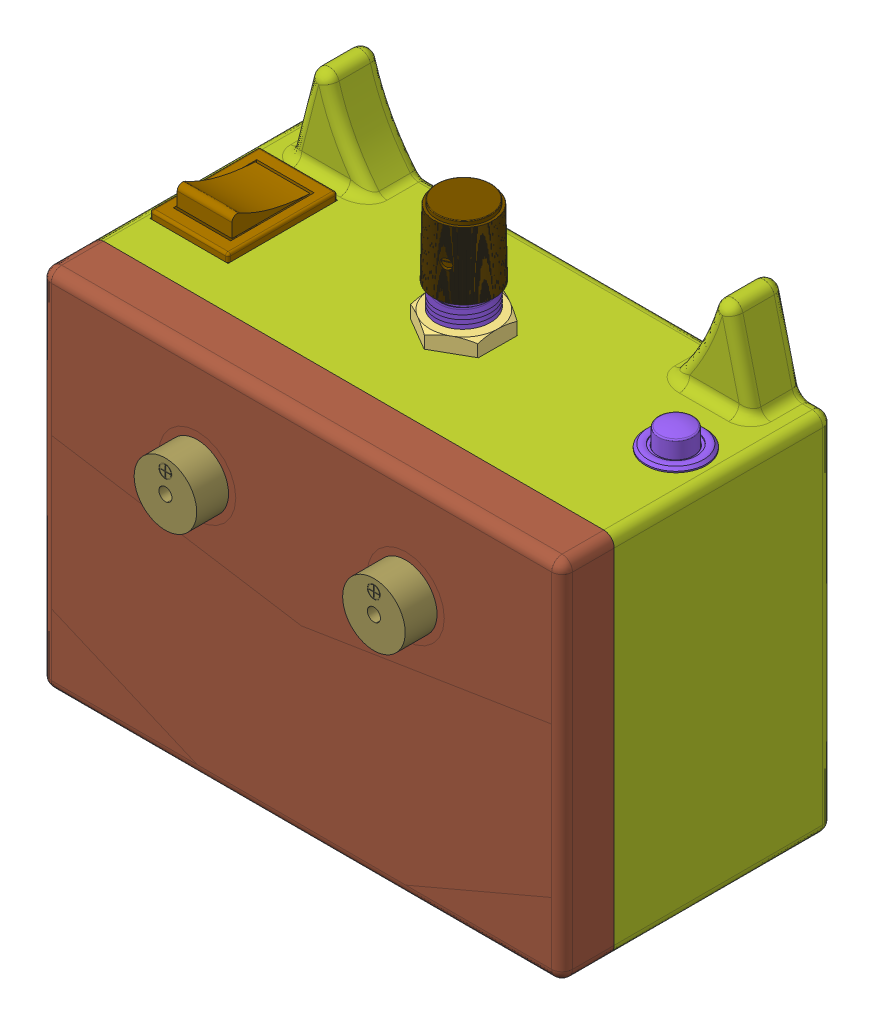
SolidWorks assembly Audio Output, configuration Default. Lengths in mm.
Overall size (102 91.24 58.1).
102 component instances, 40 part files, 22 mates.
Components (placement in the parent):
- PCB1.step-1: PCB1.step [Default] at (26.2994 -25.319 55.249) x (0 1 0) z (0 0 1) size (50.05 60.08 30.02)
  - Board.step-1: Board.step [Default] at origin size (50.05 60.08 0.41)
    - Open CASCADE STEP translator 6.8 1.1.1.step-1: Open CASCADE STEP translator 6.8 1.1.1.step [Default] at (0 0 -0.4115) size (50.05 60.08 0.41)
  - JST4.step-1: JST4.step [Default] at origin size (7.4 5.75 10.4)
    - Conn_JST_B2B-XH-A_LF_SN_eec.step-1: Conn_JST_B2B-XH-A_LF_SN_eec.step [Default] at (42.2 27 0) size (7.4 5.75 10.4)
      - 1.step-1: 1.step [Default] at (0 0.025 0) x (-1 0 0) z (0 1 0) size (7.4 10.4 5.75)
        - 1-0.step-1: 1-0.step [Default] at origin size (3.14 10.2 0.64)
        - B2B-XH-A.step-1: B2B-XH-A.step [Default] at origin size (7.4 7 5.75)
        - JST_Logo_adjustable.step-1: JST_Logo_adjustable.step [Default] at (-1.7267 5.5034 2.841) size (0.85 2.3 0.01)
  - U2.step-1: U2.step [Default] at origin size (4.51 10.4 30.02)
    - 5981934816.step-1: 5981934816.step [Default] at (24.525 10.615 0) x (1 0 0) z (0 0 1) size (1.3 10.4 0)
      - Extruded.step-1: Extruded.step [Default] at origin size (1.3 10.4 0)
    - L7805ACV.step-1: L7805ACV.step [Default] at (26.598 10.615 0) x (0 1 0) z (1 0 0) size (10.1 30.02 4.45)
  - XTAL1.step-1: XTAL1.step [Default] at origin size (4.65 11.36 3.61)
    - 5981933456.step-1: 5981933456.step [Default] at (7.9501 28.7399 0) size (4.65 11.36 1.01)
      - Extruded-1.step-1: Extruded-1.step [Default] at origin size (4.65 11.36 1.01)
    - 5981933376.step-1: 5981933376.step [Default] at (7.9499 28.7399 1) size (3.7 10.05 2.6)
      - Extruded-2.step-1: Extruded-2.step [Default] at origin size (3.7 10.05 2.6)
  - U1.step-1: U1.step [Default] at origin size (9.68 34.6 7.3)
    - atmega328p-pu.step-1: atmega328p-pu.step [Default] at (18.5 51.4 0) x (0 -1 0) z (-1 0 0) size (34.6 7.3 9.68)
  - R2.step-1: R2.step [Default] at origin size (2.5 7 2.5)
    - 5981932096.step-1: 5981932096.step [Default] at (7.5999 50.5249 1.25) x (1 0 0) z (0 -1 0) size (2.5 2.5 7)
      - Cylinder.step-1: Cylinder.step [Default] at origin size (2.5 2.5 7)
  - R1.step-1: R1.step [Default] at origin size (7 2.5 2.5)
    - 5981930976.step-1: 5981930976.step [Default] at (38.0251 34.4999 1.25) x (0 1 0) z (1 0 0) size (2.5 2.5 7)
      - Cylinder-3.step-1: Cylinder-3.step [Default] at origin size (2.5 2.5 7)
  - Q1.step-1: Q1.step [Default] at origin size (3.05 4.08 12.8)
    - BC547-B.step-1: BC547-B.step [Default] at (39.7 49.2764 5) x (0 -1 0) z (0 0 -1) size (4.08 3.05 12.8)
  - JST3.step-1: JST3.step [Default] at origin size (3.4 8.75 6.85)
    - Conn_Harwin_M30-6100646_eec.step-1: Conn_Harwin_M30-6100646_eec.step [Default] at (30.37 24.2 0) x (0 1 0) z (0 0 1) size (8.75 3.4 6.85)
      - M30-610XXXX_MOULDING.step-1: M30-610XXXX_MOULDING.step [Default] at (4.375 1.7 4.3) size (8.75 3.4 4.55)
      - M30-610XXXX_PIN.step-1: M30-610XXXX_PIN.step [Default] at (-2.95 0.675 -2.3) x (-1 0 0) z (0 0 1) size (0.35 0.35 6)
      - M30-610XXXX_PIN.step-2: M30-610XXXX_PIN.step [Default] at (-1.7 0.675 -2.3) x (-1 0 0) z (0 0 1) size (0.35 0.35 6)
      - M30-610XXXX_PIN.step-3: M30-610XXXX_PIN.step [Default] at (-0.45 0.675 -2.3) x (-1 0 0) z (0 0 1) size (0.35 0.35 6)
      - M30-610XXXX_PIN.step-4: M30-610XXXX_PIN.step [Default] at (0.8 0.675 -2.3) x (-1 0 0) z (0 0 1) size (0.35 0.35 6)
      - M30-610XXXX_PIN.step-5: M30-610XXXX_PIN.step [Default] at (2.05 0.675 -2.3) x (-1 0 0) z (0 0 1) size (0.35 0.35 6)
      - M30-610XXXX_PIN.step-6: M30-610XXXX_PIN.step [Default] at (3.3 0.675 -2.3) x (-1 0 0) z (0 0 1) size (0.35 0.35 6)
      - Harwin.step-1: Harwin.step [Default] at (-3.7429 -1.6985 2.1984) x (1 0 0) z (0 -1 0) size (2.66 0.49 0)
  - JST2.step-1: JST2.step [Default] at origin size (7.4 5.75 10.4)
    - Conn_JST_B2B-XH-A_LF_SN_eec.step-1: Conn_JST_B2B-XH-A_LF_SN_eec.step [Default] at (29.475 48.15 0) size (7.4 5.75 10.4)
      - 1.step-1: 1.step [Default] at (0 0.025 0) x (-1 0 0) z (0 1 0) size (7.4 10.4 5.75)
        - 1-0.step-1: 1-0.step [Default] at origin size (3.14 10.2 0.64)
        - B2B-XH-A.step-1: B2B-XH-A.step [Default] at origin size (7.4 7 5.75)
        - JST_Logo_adjustable.step-1: JST_Logo_adjustable.step [Default] at (-1.7267 5.5034 2.841) size (0.85 2.3 0.01)
  - JST1.step-1: JST1.step [Default] at origin size (7.4 5.75 10.4)
    - Conn_JST_B2B-XH-A_LF_SN_eec.step-1: Conn_JST_B2B-XH-A_LF_SN_eec.step [Default] at (15.625 8.65 0) x (-1 0 0) z (0 0 1) size (7.4 5.75 10.4)
      - 1.step-1: 1.step [Default] at (0 0.025 0) x (-1 0 0) z (0 1 0) size (7.4 10.4 5.75)
        - 1-0.step-1: 1-0.step [Default] at origin size (3.14 10.2 0.64)
        - B2B-XH-A.step-1: B2B-XH-A.step [Default] at origin size (7.4 7 5.75)
        - JST_Logo_adjustable.step-1: JST_Logo_adjustable.step [Default] at (-1.7267 5.5034 2.841) size (0.85 2.3 0.01)
  - C6.step-1: C6.step [Default] at origin size (8 8 14.5)
    - Aluminum_electrolytic_capacitor_radial_D8_H11.5_PinD0.6_Pitch3.5_nominal_black.step-1: Aluminum_electrolytic_capacitor_radial_D8_H11.5_PinD0.6_Pitch3.5_nominal_black.step [Default] at (42.175 17.25 0) x (-1 0 0) z (0 0 1) size (1.1 2.07 11.1)
    - Aluminum_electrolytic_capacitor_radial_D8_H11.5_PinD0.6_Pitch3.5_nominal_black-4.step-1: Aluminum_electrolytic_capacitor_radial_D8_H11.5_PinD0.6_Pitch3.5_nominal_black-4.step [Default] at (42.175 17.25 0) x (-1 0 0) z (0 0 1) size (7.86 8 11.1)
    - Aluminum_electrolytic_capacitor_radial_D8_H11.5_PinD0.6_Pitch3.5_nominal_black-5.step-1: Aluminum_electrolytic_capacitor_radial_D8_H11.5_PinD0.6_Pitch3.5_nominal_black-5.step [Default] at (42.175 17.25 0) x (-1 0 0) z (0 0 1) size (7.8 7.8 10.9)
    - Aluminum_electrolytic_capacitor_radial_D8_H11.5_PinD0.6_Pitch3.5_nominal_black-6.step-1: Aluminum_electrolytic_capacitor_radial_D8_H11.5_PinD0.6_Pitch3.5_nominal_black-6.step [Default] at (42.175 17.25 0) x (-1 0 0) z (0 0 1) size (7.4 7.4 1.6)
    - Aluminum_electrolytic_capacitor_radial_D8_H11.5_PinD0.6_Pitch3.5_nominal_black-7.step-1: Aluminum_electrolytic_capacitor_radial_D8_H11.5_PinD0.6_Pitch3.5_nominal_black-7.step [Default] at (42.175 17.25 0) x (-1 0 0) z (0 0 1) size (4.1 0.6 3)
  - C5.step-1: C5.step [Default] at origin size (8 8 14.5)
    - Aluminum_electrolytic_capacitor_radial_D8_H11.5_PinD0.6_Pitch3.5_nominal_black.step-1: Aluminum_electrolytic_capacitor_radial_D8_H11.5_PinD0.6_Pitch3.5_nominal_black.step [Default] at (35.75 10.125 0) size (1.1 2.07 11.1)
    - Aluminum_electrolytic_capacitor_radial_D8_H11.5_PinD0.6_Pitch3.5_nominal_black-4.step-1: Aluminum_electrolytic_capacitor_radial_D8_H11.5_PinD0.6_Pitch3.5_nominal_black-4.step [Default] at (35.75 10.125 0) size (7.86 8 11.1)
    - Aluminum_electrolytic_capacitor_radial_D8_H11.5_PinD0.6_Pitch3.5_nominal_black-5.step-1: Aluminum_electrolytic_capacitor_radial_D8_H11.5_PinD0.6_Pitch3.5_nominal_black-5.step [Default] at (35.75 10.125 0) size (7.8 7.8 10.9)
    - Aluminum_electrolytic_capacitor_radial_D8_H11.5_PinD0.6_Pitch3.5_nominal_black-6.step-1: Aluminum_electrolytic_capacitor_radial_D8_H11.5_PinD0.6_Pitch3.5_nominal_black-6.step [Default] at (35.75 10.125 0) size (7.4 7.4 1.6)
    - Aluminum_electrolytic_capacitor_radial_D8_H11.5_PinD0.6_Pitch3.5_nominal_black-7.step-1: Aluminum_electrolytic_capacitor_radial_D8_H11.5_PinD0.6_Pitch3.5_nominal_black-7.step [Default] at (35.75 10.125 0) size (4.1 0.6 3)
  - C3.step-1: C3.step [Default] at origin size (8 8 14.5)
    - Aluminum_electrolytic_capacitor_radial_D8_H11.5_PinD0.6_Pitch3.5_nominal_black.step-1: Aluminum_electrolytic_capacitor_radial_D8_H11.5_PinD0.6_Pitch3.5_nominal_black.step [Default] at (30.75 38.1 0) x (0 1 0) z (0 0 1) size (1.1 2.07 11.1)
    - Aluminum_electrolytic_capacitor_radial_D8_H11.5_PinD0.6_Pitch3.5_nominal_black-4.step-1: Aluminum_electrolytic_capacitor_radial_D8_H11.5_PinD0.6_Pitch3.5_nominal_black-4.step [Default] at (30.75 38.1 0) x (0 1 0) z (0 0 1) size (7.86 8 11.1)
    - Aluminum_electrolytic_capacitor_radial_D8_H11.5_PinD0.6_Pitch3.5_nominal_black-5.step-1: Aluminum_electrolytic_capacitor_radial_D8_H11.5_PinD0.6_Pitch3.5_nominal_black-5.step [Default] at (30.75 38.1 0) x (0 1 0) z (0 0 1) size (7.8 7.8 10.9)
    - Aluminum_electrolytic_capacitor_radial_D8_H11.5_PinD0.6_Pitch3.5_nominal_black-6.step-1: Aluminum_electrolytic_capacitor_radial_D8_H11.5_PinD0.6_Pitch3.5_nominal_black-6.step [Default] at (30.75 38.1 0) x (0 1 0) z (0 0 1) size (7.4 7.4 1.6)
    - Aluminum_electrolytic_capacitor_radial_D8_H11.5_PinD0.6_Pitch3.5_nominal_black-7.step-1: Aluminum_electrolytic_capacitor_radial_D8_H11.5_PinD0.6_Pitch3.5_nominal_black-7.step [Default] at (30.75 38.1 0) x (0 1 0) z (0 0 1) size (4.1 0.6 3)
  - C2.step-1: C2.step [Default] at origin size (5.5 2.51 10)
    - Cap_Murata_RCE5C2A3R0C0K1H03B_eec.step-1: Cap_Murata_RCE5C2A3R0C0K1H03B_eec.step [Default] at (7.8 18.95 0) x (1 0 0) z (0 0 1) size (5.5 2.51 10)
      - body.step-1: body.step [Default] at origin size (3.6 2.5 4.1)
      - leads.step-1: leads.step [Default] at origin size (5.5 0.5 6.65)
      - logo.step-1: logo.step [Default] at (0 -1.25 8.5) x (1 0 0) z (0 -1 0) size (1.98 0.46 0.01)
  - C1.step-1: C1.step [Default] at origin size (5.5 2.51 10)
    - Cap_Murata_RCE5C2A3R0C0K1H03B_eec.step-1: Cap_Murata_RCE5C2A3R0C0K1H03B_eec.step [Default] at (8.3 38.2 0) x (1 0 0) z (0 0 1) size (5.5 2.51 10)
      - body.step-1: body.step [Default] at origin size (3.6 2.5 4.1)
      - leads.step-1: leads.step [Default] at origin size (5.5 0.5 6.65)
      - logo.step-1: logo.step [Default] at (0 -1.25 8.5) x (1 0 0) z (0 -1 0) size (1.98 0.46 0.01)
  - Free-Models.step-1: Free-Models.step [Default] at origin size (10.56 2.5 4.8)
    - Diode_1N4001.step-1: Diode_1N4001.step [Default] at (44.28 43.65 0) x (-1 0 0) z (0 0 1) size (10.56 2.5 4.8)
- Part49^Audio Output-1: Part49^Audio Output [Default] at (26.2994 -25.319 55.249) x (0 1 0) z (0 0 1) size (86.95 102 42.04) (virtual)
- Bouton poussoir-2: Bouton poussoir [Défaut] at (37.5441 27.181 52.749) size (11.58 13 11.58)
- 64_Switch.step-1: 64_Switch.step [Default] at (-51.0981 24.181 63.0135) x (0 0 -1) z (1 0 0) size (23 26.97 15)
- BATTARY HOLDER-1: BATTARY HOLDER [По умолчанию] at (-3.7956 -0.254 51.249) x (-1 0 0) z (0 -1 0) size (54.61 19.5 29.97)
- Part1^Audio Output-1: Part1^Audio Output [Default] at (26.2994 -25.319 73.249) x (0 1 0) z (0 0 1) size (70 100 27.75) (virtual)
- TMB12A05.step-1: TMB12A05.step [Default] at (-23.7756 10.891 79.839) size (12 12 11.85)
- TMB12A05.step-2: TMB12A05.step [Default] at (16.2244 10.891 79.839) size (12 12 11.85)
- 100 ohm Sigle Potentiometer Assembly.STEP-1: 100 ohm Sigle Potentiometer Assembly.STEP [Default] at (-2.4938 19.2483 61.2667) x (-0.926821 0 0.375502) z (0 -1 0) size (25.4 26.22 29.59)
  - PCB.STEP-1: PCB.STEP [Default] at (-2.7005 7.9259 -11.5277) size (16.64 19.94 1.27)
  - Plate.STEP-1: Plate.STEP [Default] at (-2.7005 7.9259 -12.1627) size (17.02 10.92 0.64)
  - Wire_Tab.STEP-1: Wire_Tab.STEP [Default] at (-5.8755 14.4664 -10.2577) x (0 1 0) z (0 0 1) size (6.98 3.81 4.44)
  - Wire_Tab.STEP-2: Wire_Tab.STEP [Default] at (-0.7955 14.4664 -10.2577) x (0 1 0) z (0 0 1) size (6.98 3.81 4.44)
  - Wire_Tab.STEP-3: Wire_Tab.STEP [Default] at (4.2845 14.4664 -10.2577) x (0 1 0) z (0 0 1) size (6.98 3.81 4.44)
  - Rivet.STEP-1: Rivet.STEP [Default] at (-7.7805 16.3714 -9.6227) x (-0.923728 -0.383049 0) z (0 0 -1) size (2.54 3.49 2.22)
  - Rivet.STEP-2: Rivet.STEP [Default] at (-2.7005 16.3714 -9.6227) x (-0.923728 -0.383049 0) z (0 0 -1) size (2.54 3.49 2.22)
  - Rivet.STEP-3: Rivet.STEP [Default] at (2.3795 16.3714 -9.6227) x (-0.923728 -0.383049 0) z (0 0 -1) size (2.54 3.49 2.22)
  - Barrell2.STEP-1: Barrell2.STEP [Default] at (-2.7005 7.9259 -21.6877) size (10.47 10.4 9.53)
  - Potentiometer Knob.STEP-1: Potentiometer Knob.STEP [Default] at (-10.5959 -2.0877 -35.9117) x (-1 0 0) z (0 0 -1) size (11.86 13.59 13.46)
  - Shaft.STEP-1: Shaft.STEP [Default] at (-2.7005 7.9259 -14.3217) x (-0.923728 -0.383049 0) z (0 0 -1) size (5.97 5.97 23.75)
  - Washer^100 ohm Sigle Potentiometer Assembly.STEP-1: Washer^100 ohm Sigle Potentiometer Assembly.STEP [Default] at (-2.7005 7.9259 -13.4327) x (-1 0 0) z (0 0 -1) size (14.25 14.25 0.89)
  - hex nut jam_am_B18.2.4.5M - Hex jam nut,  M8 x 1.25 --D-N.STEP-1: hex nut jam_am_B18.2.4.5M - Hex jam nut,  M8 x 1.25 --D-N.STEP [Default] at (-2.7005 7.9259 -18.3217) x (0.923728 0.383049 0) z (0 0 -1) size (15.02 15.02 4.01)
  - Level Indicator Plate^100 ohm Sigle Potentiometer Assembly.STEP-1: Level Indicator Plate^100 ohm Sigle Potentiometer Assembly.STEP [Default] at (-2.7005 7.9259 -12.1627) x (-1 0 0) z (0 0 -1) size (25.4 25.4 1.27)
Mates (geometry in assembly coordinates):
- InPlace1: in place: plane of PCB1.step-1/Board.step-1/Open CASCADE STEP translator 6.8 1.1.1.step-1 through (26.2994 -25.319 55.249) normal (0 0 1); plane of ? through (0 0 55.249) normal (0 0 1); moOrthogonalPlaneRef_w of PCB1.step-1/Board.step-1/Open CASCADE STEP translator 6.8 1.1.1.step-1 through (26.2994 -25.319 55.249) normal (0 0 1); plane of ? through (0 0 55.249) normal (0 1 0); plane of PCB1.step-1/Board.step-1/Open CASCADE STEP translator 6.8 1.1.1.step-1 through (26.2994 -25.319 55.249) normal (0 0 1); plane of ? through (0 0 55.249) normal (1 0 0); plane of PCB1.step-1/Board.step-1/Open CASCADE STEP translator 6.8 1.1.1.step-1 through (26.2994 -25.319 55.249) normal (0 0 1); unknown of Part49^Audio Output-1
- Coincident1: coincident aligned: plane of PCB1.step-1/Board.step-1/Open CASCADE STEP translator 6.8 1.1.1.step-1; plane of Part49^Audio Output-1
- Coincident2: coincident aligned: moOrthogonalPlaneRef_w of PCB1.step-1/Board.step-1/Open CASCADE STEP translator 6.8 1.1.1.step-1 through (26.2994 -25.319 55.249) normal (-1 0 0); plane of Part49^Audio Output-1 through (26.2994 -25.319 55.249) normal (-1 0 0)
- Coincident3: coincident anti-aligned: moOrthogonalPlaneRef_w of PCB1.step-1/Board.step-1/Open CASCADE STEP translator 6.8 1.1.1.step-1 through (26.2994 -25.319 55.249) normal (0 -1 0); plane of Part49^Audio Output-1 through (26.2994 -25.319 55.249) normal (0 1 0)
- Concentric2: concentric anti-aligned: cylinder of Part49^Audio Output-1 through (37.5441 29.681 52.749) axis (0 1 0) radius 5.125; cylinder of Bouton poussoir-2 through (37.5441 34.681 52.749) axis (0 -1 0) radius 5
- Coincident12: coincident anti-aligned: plane of Part49^Audio Output-1 through (-53.7756 34.681 73.249) normal (0 1 0); plane of Bouton poussoir-2 through (37.5441 34.681 52.749) normal (0 -1 0)
- Coincident23: coincident anti-aligned: plane of Part49^Audio Output-1 through (-53.7756 34.681 73.249) normal (0 1 0); plane of 64_Switch.step-1 through (-51.0981 34.681 44.0135) normal (0 -1 0)
- Coincident27: coincident anti-aligned: line of Part49^Audio Output-1 through (-51.1081 34.681 65.0135) axis (1 0 0); line of 64_Switch.step-1 through (-36.5981 34.681 65.0135) axis (-1 0 0)
- Coincident28: coincident aligned: line of Part49^Audio Output-1 through (-36.0981 34.681 65.0135) axis (0 0 -1); line of 64_Switch.step-1 through (-36.0981 34.681 64.5135) axis (0 0 -1)
- Coincident32: coincident anti-aligned: plane of Part49^Audio Output-1 through (26.2994 -25.319 51.249) normal (0 0 -1); plane of BATTARY HOLDER-1 through (-3.7956 -0.254 51.249) normal (0 0 1)
- Coincident33: coincident anti-aligned: plane of Part49^Audio Output-1 through (25.5542 14.731 53.249) normal (0 -1 0); plane of BATTARY HOLDER-1 through (23.5094 14.731 48.749) normal (0 1 0)
- Coincident34: coincident anti-aligned: plane of Part49^Audio Output-1 through (-31.1006 16.731 53.249) normal (1 0 0); plane of BATTARY HOLDER-1 through (-31.1006 14.731 48.749) normal (-1 0 0)
- InPlace2: in place: plane of Part49^Audio Output-1 through (26.2994 -25.319 73.249) normal (0 0 1); plane of ? through (0 0 73.249) normal (0 0 1); plane of Part49^Audio Output-1 through (26.2994 -25.319 73.249) normal (0 0 1); plane of ? through (0 0 73.249) normal (0 1 0); plane of Part49^Audio Output-1 through (26.2994 -25.319 73.249) normal (0 0 1); plane of ? through (0 0 73.249) normal (1 0 0); plane of Part49^Audio Output-1 through (26.2994 -25.319 73.249) normal (0 0 1); unknown of Part1^Audio Output-1
- Coincident35: coincident aligned: plane of Part49^Audio Output-1; plane of Part1^Audio Output-1
- Coincident36: coincident aligned: moOrthogonalPlaneRef_w of Part49^Audio Output-1 through (26.2994 -25.319 73.249) normal (-1 0 0); plane of Part1^Audio Output-1 through (26.2994 -25.319 73.249) normal (-1 0 0)
- Coincident37: coincident anti-aligned: moOrthogonalPlaneRef_w of Part49^Audio Output-1 through (26.2994 -25.319 73.249) normal (0 -1 0); plane of Part1^Audio Output-1 through (26.2994 -25.319 73.249) normal (0 1 0)
- Coincident38: coincident anti-aligned: plane of Part1^Audio Output-1 through (-23.7756 14.681 80.249) normal (0 0 1); plane of TMB12A05.step-1 through (-23.7756 14.681 80.249) normal (0 0 -1)
- Concentric3: concentric anti-aligned: cylinder of Part1^Audio Output-1 through (-23.7756 14.681 80.249) axis (0 0 1) radius 6; cylinder of TMB12A05.step-1 through (-23.7756 14.681 79.849) axis (0 0 -1) radius 6
- Coincident39: coincident anti-aligned: plane of Part1^Audio Output-1 through (16.2244 14.681 80.249) normal (0 0 1); plane of TMB12A05.step-2 through (16.2244 14.681 80.249) normal (0 0 -1)
- Concentric4: concentric anti-aligned: cylinder of Part1^Audio Output-1 through (16.2244 14.681 80.249) axis (0 0 1) radius 6; cylinder of TMB12A05.step-2 through (16.2244 14.681 79.849) axis (0 0 -1) radius 6
- Coincident45: coincident anti-aligned: plane of Part49^Audio Output-1 through (-53.7756 32.681 73.249) normal (0 -1 0); plane of 100 ohm Sigle Potentiometer Assembly.STEP-1/Level Indicator Plate^100 ohm Sigle Potentiometer Assembly.STEP-1 through (-2.9671 32.681 52.9068) normal (0 1 0)
- Lock1: lock: unknown of Part49^Audio Output-1; unknown of 100 ohm Sigle Potentiometer Assembly.STEP-1/Level Indicator Plate^100 ohm Sigle Potentiometer Assembly.STEP-1
